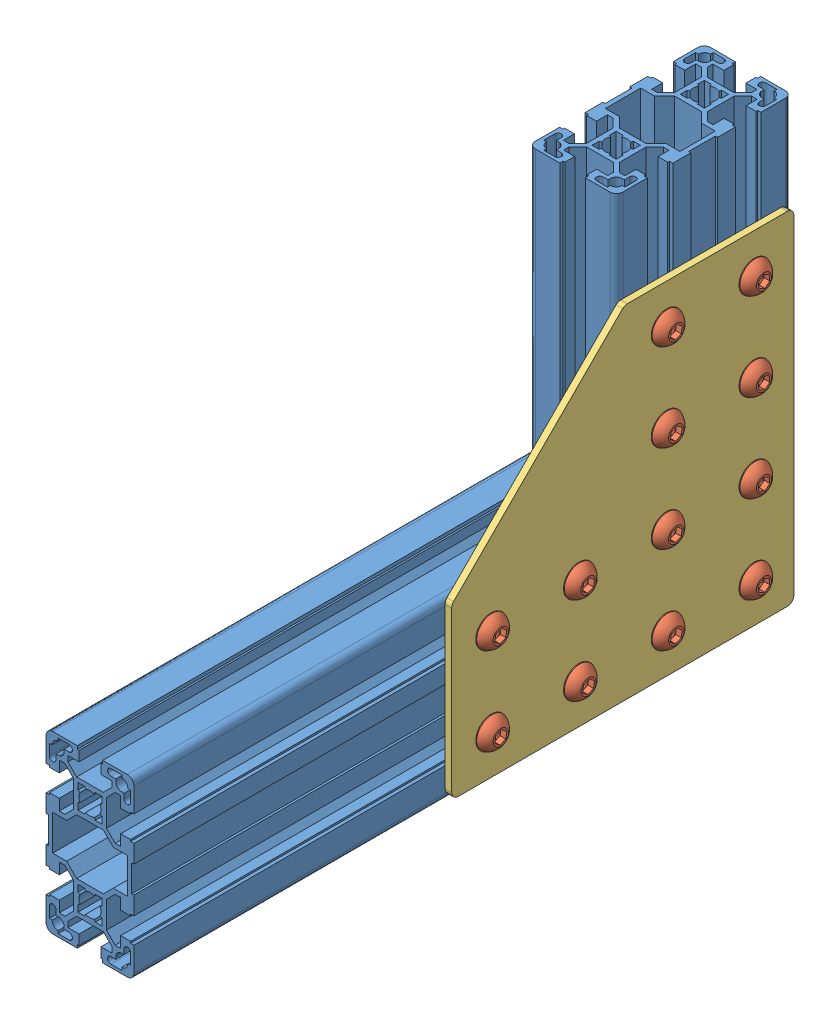
SolidWorks assembly Сборка AL-G40.160160 Г-соединитель 160х160, 40 серия, configuration По умолчанию. Lengths in mm.
Overall size (47.4 200 300).
15 component instances, 3 part files, 6 mates.
Components (placement in the parent):
- AL-PS-4080-1: AL-PS-4080 [Default] at origin size (40 80 300)
- AL-PS-4080-2: AL-PS-4080 [-01] at (0 40 -260) x (1 0 0) z (0 -1 0) size (40 80 120)
- Винт ISO 7380 - M8 x 16-1: Винт ISO 7380 - M8 x 16 [По умолчанию] at (27.4 19.8916 -159.8916) x (-1 0 0) z (0 0.924225 0.381849) size (20.4 14 14)
- Винт ISO 7380 - M8 x 16-2: Винт ISO 7380 - M8 x 16 [По умолчанию] at (27.4 -20.1084 -159.8916) x (-1 0 0) z (0 0.924225 0.381849) size (20.4 14 14)
- Винт ISO 7380 - M8 x 16-3: Винт ISO 7380 - M8 x 16 [По умолчанию] at (27.4 19.8916 -199.8916) x (-1 0 0) z (0 0.924225 0.381849) size (20.4 14 14)
- Винт ISO 7380 - M8 x 16-4: Винт ISO 7380 - M8 x 16 [По умолчанию] at (27.4 -20.1084 -199.8916) x (-1 0 0) z (0 0.924225 0.381849) size (20.4 14 14)
- Винт ISO 7380 - M8 x 16-5: Винт ISO 7380 - M8 x 16 [По умолчанию] at (27.4 -20.1084 -239.8916) x (-1 0 0) z (0 0.924225 0.381849) size (20.4 14 14)
- Винт ISO 7380 - M8 x 16-6: Винт ISO 7380 - M8 x 16 [По умолчанию] at (27.4 19.8916 -239.8916) x (-1 0 0) z (0 0.924225 0.381849) size (20.4 14 14)
- Винт ISO 7380 - M8 x 16-7: Винт ISO 7380 - M8 x 16 [По умолчанию] at (27.4 59.8916 -239.8916) x (-1 0 0) z (0 0.924225 0.381849) size (20.4 14 14)
- Винт ISO 7380 - M8 x 16-8: Винт ISO 7380 - M8 x 16 [По умолчанию] at (27.4 99.8916 -239.8916) x (-1 0 0) z (0 0.924225 0.381849) size (20.4 14 14)
- Винт ISO 7380 - M8 x 16-13: Винт ISO 7380 - M8 x 16 [По умолчанию] at (27.4 59.8916 -279.8916) x (-1 0 0) z (0 -0.924225 0.381849) size (20.4 14 14)
- Винт ISO 7380 - M8 x 16-14: Винт ISO 7380 - M8 x 16 [По умолчанию] at (27.4 99.8916 -279.8916) x (-1 0 0) z (0 -0.924225 0.381849) size (20.4 14 14)
- Винт ISO 7380 - M8 x 16-16: Винт ISO 7380 - M8 x 16 [По умолчанию] at (27.4 19.8916 -279.8916) x (-1 0 0) z (0 -0.924225 0.381849) size (20.4 14 14)
- Винт ISO 7380 - M8 x 16-17: Винт ISO 7380 - M8 x 16 [По умолчанию] at (27.4 -20.1084 -279.8916) x (-1 0 0) z (0 -0.924225 0.381849) size (20.4 14 14)
- AL-G40.160160 Г-соединитель 160х160, 40 серия-1: AL-G40.160160 Г-соединитель 160х160, 40 серия [По умолчанию] at (19.2253 41.3042 -219.0299) x (0 0 1) z (0 1 0) size (156 3 156)
Mates (geometry in assembly coordinates):
- Совпадение1: coincident aligned: plane of AL-PS-4080-1 through (20 25.9084 -300) normal (1 0 0); plane of AL-PS-4080-2 through (20 160 -234.0916) normal (1 0 0)
- Совпадение2: coincident anti-aligned: plane of AL-PS-4080-1 through (17 40 -300) normal (0 1 0); plane of AL-PS-4080-2 through (-17 40 -297) normal (0 -1 0)
- Совпадение112: coincident aligned: plane of AL-PS-4080-1 through (-17 -37 -300) normal (0 0 -1); plane of AL-PS-4080-2 through (17 160 -300) normal (0 0 -1)
- Концентричный1: concentric: cylinder of Винт ISO 7380 - M8 x 16-2 through (7 -20.1084 -159.8916) axis (1 0 0) radius 4; cylinder of AL-G40.160160 Г-соединитель 160х160, 40 серия-1 through (23 -20.1084 -159.8916) axis (-1 0 0) radius 4.1
- Концентричный2: concentric: cylinder of Винт ISO 7380 - M8 x 16-14 through (7 99.8916 -279.8916) axis (1 0 0) radius 4; cylinder of AL-G40.160160 Г-соединитель 160х160, 40 серия-1 through (23 99.8916 -279.8916) axis (-1 0 0) radius 4.1
- Совпадение113: coincident anti-aligned: plane of AL-PS-4080-1 through (20 25.9084 -300) normal (1 0 0); plane of AL-G40.160160 Г-соединитель 160х160, 40 серия-1 through (20 114.8916 -221.9627) normal (-1 0 0)
